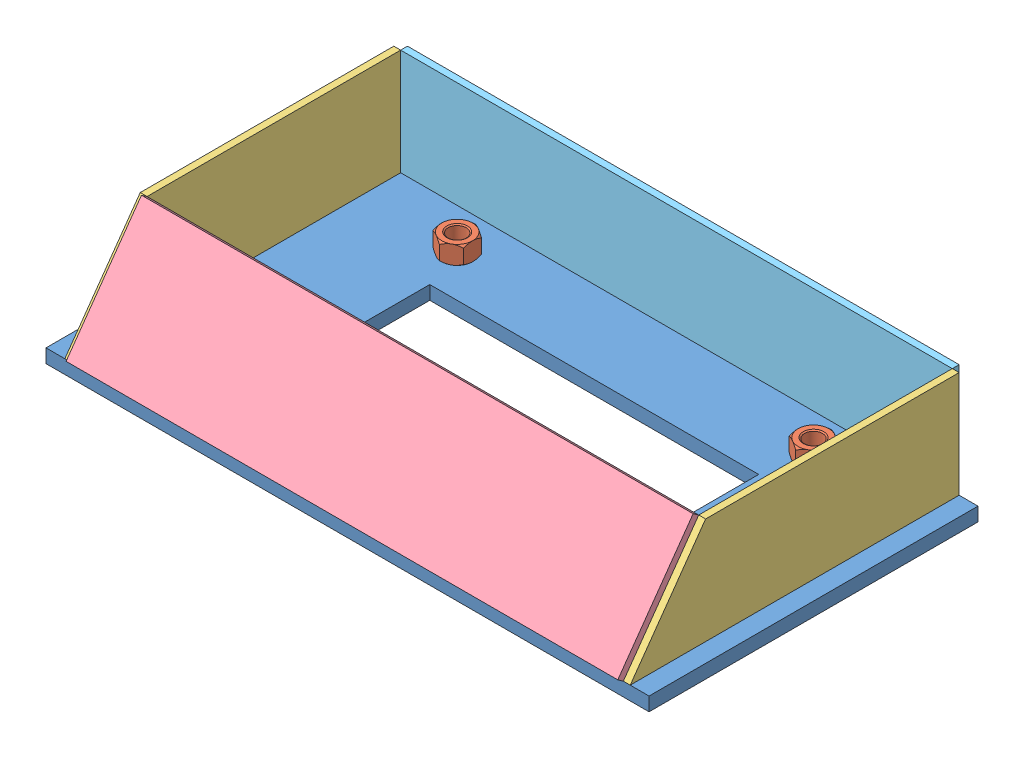
SolidWorks assembly Hopper Interface Saddle Weldment, configuration Default. Lengths in mm.
Overall size (558.8 114.77 316.33).
9 component instances, 5 part files, 15 mates.
Components (placement in the parent):
- Hopper Interface Plate 1 piece-1: Hopper Interface Plate 1 piece [Default] at (-327.1904 -17.2713 -41.5) size (558.8 12.7 304.8)
- hex nut_ai-2: hex nut_ai [HNUT 0.7500-10-D-C] at (-272.3906 12.3197 -50.2645) x (1 0 0) z (0 1 0) size (28.57 33 16.89)
- hex nut_ai-3: hex nut_ai [HNUT 0.7500-10-D-C] at (57.8094 12.3197 -50.2645) x (1 0 0) z (0 1 0) size (28.57 33 16.89)
- hex nut_ai-4: hex nut_ai [HNUT 0.7500-10-D-C] at (57.8094 12.3197 178.3355) x (1 0 0) z (0 1 0) size (28.57 33 16.89)
- hex nut_ai-5: hex nut_ai [HNUT 0.7500-10-D-C] at (-272.3906 12.3197 178.3355) x (1 0 0) z (0 1 0) size (28.57 33 16.89)
- Saddle Side Panel-1: Saddle Side Panel [Default] at (148.2969 -4.5713 216.4355) x (0 0 -1) z (0 -1 0) size (304.8 6.35 98.42)
- Saddle Side Panel-2: Saddle Side Panel [Default] at (-369.2281 -4.5713 216.4355) x (0 0 -1) z (0 -1 0) size (304.8 6.35 98.42)
- Saddle Back plate-1: Saddle Back plate [Default] at (-362.8781 -4.5713 216.4355) x (1 0 0) z (0 -0.815507 0.578747) size (511.18 6.35 120.65)
- Saddle Front Plate-1: Saddle Front Plate [Default] at (-362.8781 -4.5713 -94.7145) x (1 0 0) z (0 -1 0) size (511.18 6.35 98.42)
Mates (geometry in assembly coordinates):
- Concentric11: concentric aligned: cylinder of Hopper Interface Plate 1 piece-1 through (-272.3906 -17.2713 -50.2645) axis (0 1 0) radius 10.287; cylinder of hex nut_ai-2 through (-272.3906 -12.7178 -50.2645) axis (0 1 0) radius 9.525
- Coincident11: coincident anti-aligned: plane of Hopper Interface Plate 1 piece-1 through (-327.1904 -4.5713 -41.5) normal (0 1 0); plane of hex nut_ai-2 through (-272.3906 -4.5713 -66.7622) normal (0 -1 0)
- Concentric21: concentric aligned: cylinder of Hopper Interface Plate 1 piece-1 through (57.8094 -17.2713 -50.2645) axis (0 1 0) radius 10.287; cylinder of hex nut_ai-3 through (57.8094 -12.7178 -50.2645) axis (0 1 0) radius 9.525
- Coincident21: coincident anti-aligned: plane of Hopper Interface Plate 1 piece-1 through (-327.1904 -4.5713 -41.5) normal (0 1 0); plane of hex nut_ai-3 through (57.8094 -4.5713 -66.7622) normal (0 -1 0)
- Concentric31: concentric aligned: cylinder of Hopper Interface Plate 1 piece-1 through (57.8094 -17.2713 178.3355) axis (0 1 0) radius 10.287; cylinder of hex nut_ai-4 through (57.8094 -12.7178 178.3355) axis (0 1 0) radius 9.525
- Coincident31: coincident anti-aligned: plane of Hopper Interface Plate 1 piece-1 through (-327.1904 -4.5713 -41.5) normal (0 1 0); plane of hex nut_ai-4 through (57.8094 -4.5713 161.8378) normal (0 -1 0)
- Concentric41: concentric aligned: cylinder of Hopper Interface Plate 1 piece-1 through (-272.3906 -17.2713 178.3355) axis (0 1 0) radius 10.287; cylinder of hex nut_ai-5 through (-272.3906 -12.7178 178.3355) axis (0 1 0) radius 9.525
- Coincident41: coincident anti-aligned: plane of Hopper Interface Plate 1 piece-1 through (-327.1904 -4.5713 -41.5) normal (0 1 0); plane of hex nut_ai-5 through (-272.3906 -4.5713 161.8378) normal (0 -1 0)
- Coincident17: coincident: plane of Hopper Interface Plate 1 piece-1 through (-327.1904 -4.5713 -41.5) normal (0 1 0); plane of Saddle Front Plate-1 through (-386.6906 -4.5713 -88.3645) normal (0 -1 0)
- Distance1: distance = 23.8125 mm aligned: plane of Hopper Interface Plate 1 piece-1 through (172.1094 -4.5713 -88.3645) normal (1 0 0); plane of Saddle Front Plate-1 through (148.2969 -4.5713 -88.3645) normal (1 0 0)
- Coincident43: coincident anti-aligned: plane of Hopper Interface Plate 1 piece-1 through (-327.1904 -4.5713 -41.5) normal (0 1 0); plane of Saddle Side Panel-1 through (154.6469 -4.5713 216.4355) normal (0 -1 0)
- Coincident44: coincident aligned: line of Saddle Side Panel-1 through (148.2969 -4.5713 -88.3645) axis (0 1 0); line of Saddle Front Plate-1 through (148.2969 -4.5713 -88.3645) axis (0 1 0)
- Coincident45: coincident anti-aligned: plane of Hopper Interface Plate 1 piece-1 through (-327.1904 -4.5713 -41.5) normal (0 1 0); plane of Saddle Side Panel-2 through (-362.8781 -4.5713 216.4355) normal (0 -1 0)
- Coincident46: coincident anti-aligned: line of Saddle Side Panel-2 through (-362.8781 -4.5713 -88.3645) axis (0 1 0); line of Saddle Front Plate-1 through (-362.8781 93.8537 -88.3645) axis (0 -1 0)
- Coincident47: coincident anti-aligned: line of Saddle Side Panel-1 through (148.2969 93.8537 146.5855) axis (0 -0.815507 0.578747); line of Saddle Back plate-1 through (148.2969 -4.5713 216.4355) axis (0 0.815507 -0.578747)
